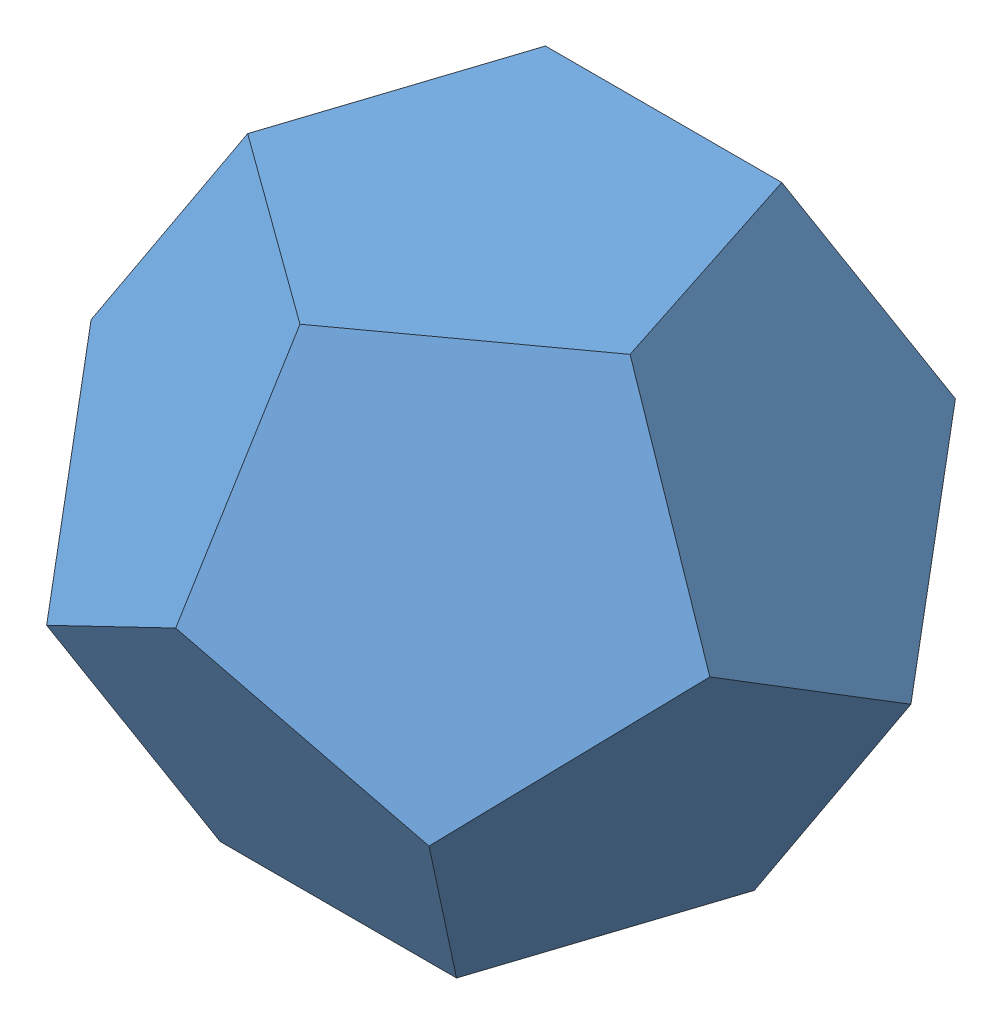
SolidWorks assembly Dodecahedron, configuration Default. Lengths in mm.
Overall size (74.35 78.17 75.32).
12 component instances, 1 part files, 26 mates.
Components (placement in the parent):
- Pentagon-1: Pentagon [Default] at origin size (41.1 2.54 39.09)
- Pentagon-2: Pentagon [Default] at (-14.8694 15.6346 -20.466) x (0.5 -0.850651 0.16246) z (-0.688191 -0.276393 0.67082) size (41.1 2.54 39.09)
- Pentagon-3: Pentagon [Default] at (-24.0592 15.6346 7.8173) x (0.5 -0.525731 0.688191) z (-0.16246 0.723607 0.67082) size (41.1 2.54 39.09)
- Pentagon-4: Pentagon [Default] at (24.0592 40.932 -7.8173) x (0.5 -0.525731 0.688191) z (0.16246 -0.723607 -0.67082) size (41.1 2.54 39.09)
- Pentagon-5: Pentagon [Default] at (24.0592 15.6346 7.8173) x (0.5 0.525731 -0.688191) z (0.16246 0.723607 0.67082) size (41.1 2.54 39.09)
- Pentagon-6: Pentagon [Default] at (0 15.6346 25.2974) x (0.809017 -0.525731 -0.262866) z (0.587785 0.723607 0.361803) size (41.1 2.54 39.09)
- Pentagon-7: Pentagon [Default] at (13.5341 39.7961 18.628) x (0.809017 -0.525731 -0.262866) z (-0.262866 -0.723607 0.638197) size (41.1 2.54 39.09)
- Pentagon-8: Pentagon [Default] at (0 54.0266 0) x (0.809017 0 0.587785) z (-0.587785 0 0.809017) size (41.1 2.54 39.09)
- Pentagon-9: Pentagon [Default] at (-21.8986 39.7961 -7.1153) x (0.5 0.850651 -0.16246) z (-0.16246 0.276393 0.947214) size (41.1 2.54 39.09)
- Pentagon-10: Pentagon [Default] at (0 39.7961 -23.0255) x (1 0 0) z (0 0.894427 0.447214) size (41.1 2.54 39.09)
- Pentagon-11: Pentagon [Default] at (14.8694 15.6346 -20.466) x (0.5 0.850651 -0.16246) z (0.688191 -0.276393 0.67082) size (41.1 2.54 39.09)
- Pentagon-12: Pentagon [Default] at (-13.5341 39.7961 18.628) x (0.809017 0.525731 0.262866) z (0.262866 -0.723607 0.638197) size (41.1 2.54 39.09)
Mates (geometry in assembly coordinates):
- Coincident17: coincident: point of Pentagon-6
- Coincident19: coincident: line of Pentagon-1 through (-12.7 0 17.4801) axis (1 0 0); line of Pentagon-6 through (12.7 0 17.4801) axis (-1 0 0)
- Coincident20: coincident: point of Pentagon-1; point of Pentagon-3
- Coincident21: coincident: line of Pentagon-1 through (-20.549 0 -6.6768) axis (0.309017 0 0.951057); line of Pentagon-3 through (-12.7 0 17.4801) axis (-0.309017 0 -0.951057)
- Coincident22: coincident: point of Pentagon-1; point of Pentagon-2
- Coincident23: coincident: line of Pentagon-1 through (0 0 -21.6065) axis (-0.809017 0 0.587785); line of Pentagon-2 through (-20.549 0 -6.6768) axis (0.809017 0 -0.587785)
- Coincident24: coincident: point of Pentagon-1; point of Pentagon-5
- Coincident25: coincident: point of Pentagon-1; point of Pentagon-11
- Coincident26: coincident: line of Pentagon-1 through (20.549 0 -6.6768) axis (-0.809017 0 -0.587785); line of Pentagon-11 through (0 0 -21.6065) axis (0.809017 0 0.587785)
- Coincident27: coincident: line of Pentagon-1 through (12.7 0 17.4801) axis (0.309017 0 -0.951057); line of Pentagon-5 through (20.549 0 -6.6768) axis (-0.309017 0 0.951057)
- Coincident28: coincident: line of Pentagon-5 through (33.249 21.6065 -10.8033) axis (-0.5 -0.850651 0.16246); line of Pentagon-11 through (20.549 0 -6.6768) axis (0.5 0.850651 -0.16246)
- Coincident29: coincident: line of Pentagon-2 through (0 0 -21.6065) axis (0 0.850651 -0.525731); line of Pentagon-11 through (0 21.6065 -34.9601) axis (0 -0.850651 0.525731)
- Coincident30: coincident: line of Pentagon-2 through (-33.249 21.6065 -10.8033) axis (0.5 -0.850651 0.16246); line of Pentagon-3 through (-20.549 0 -6.6768) axis (-0.5 0.850651 -0.16246)
- Coincident35: coincident: line of Pentagon-2 through (-20.549 34.9601 -28.2833) axis (-0.5 -0.525731 0.688191); line of Pentagon-9 through (-20.549 34.9601 -28.2833) axis (-0.5 -0.525731 0.688191)
- Coincident36: coincident: line of Pentagon-2 through (0 21.6065 -34.9601) axis (-0.809017 0.525731 0.262866); line of Pentagon-10 through (0 21.6065 -34.9601) axis (-0.809017 0.525731 0.262866)
- Coincident37: coincident: line of Pentagon-9 through (-12.7 56.5666 -17.4801) axis (-0.309017 -0.850651 -0.425325); line of Pentagon-10 through (-20.549 34.9601 -28.2833) axis (0.309017 0.850651 0.425325)
- Coincident38: coincident: line of Pentagon-8 through (12.7 56.5666 -17.4801) axis (-1 0 0); line of Pentagon-10 through (-12.7 56.5666 -17.4801) axis (1 0 0)
- Parallel6: parallel: plane of Pentagon-8 through (0 56.5666 0) normal (0 1 0); plane of assembly through (0 0 0) normal (0 1 0)
- Coincident41: coincident: line of Pentagon-8 through (-12.7 56.5666 -17.4801) axis (-0.309017 0 0.951057); line of Pentagon-9 through (-20.549 56.5666 6.6768) axis (0.309017 0 -0.951057)
- Coincident45: coincident: line of Pentagon-4 through (20.549 56.5666 6.6768) axis (-0.309017 0 -0.951057); line of Pentagon-8 through (20.549 56.5666 6.6768) axis (-0.309017 0 -0.951057)
- Coincident46: coincident: line of Pentagon-4 through (12.7 56.5666 -17.4801) axis (0.309017 -0.850651 -0.425325); line of Pentagon-10 through (12.7 56.5666 -17.4801) axis (0.309017 -0.850651 -0.425325)
- Coincident47: coincident: line of Pentagon-7 through (20.549 56.5666 6.6768) axis (-0.809017 0 0.587785); line of Pentagon-8 through (0 56.5666 21.6065) axis (0.809017 0 -0.587785)
- Coincident48: coincident: line of Pentagon-4 through (33.249 34.9601 10.8033) axis (-0.5 0.850651 -0.16246); line of Pentagon-7 through (33.249 34.9601 10.8033) axis (-0.5 0.850651 -0.16246)
- Coincident49: coincident: line of Pentagon-8 through (-20.549 56.5666 6.6768) axis (0.809017 0 0.587785); line of Pentagon-12 through (0 56.5666 21.6065) axis (-0.809017 0 -0.587785)
- Coincident50: coincident: line of Pentagon-9 through (-33.249 34.9601 10.8033) axis (0.5 0.850651 -0.16246); line of Pentagon-12 through (-20.549 56.5666 6.6768) axis (-0.5 -0.850651 0.16246)
- Parallel11: parallel: plane of Pentagon-6 through (0 15.6346 25.2974) normal (0 -0.447214 0.894427); plane of Pentagon-10 through (0 39.7961 -23.0255) normal (0 -0.447214 0.894427)
